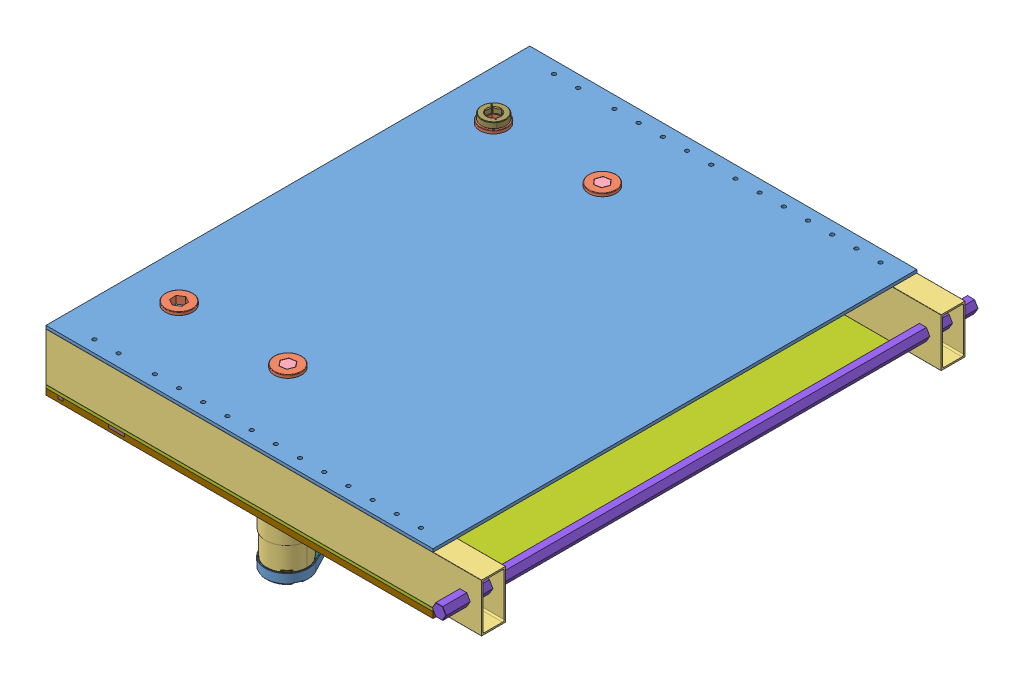
SolidWorks assembly ShooterAssem3, configuration Default. Lengths in mm.
Overall size (477.37 191.98 558.8).
70 component instances, 21 part files, 57 mates.
Components (placement in the parent):
- ShooterPlate3-1: ShooterPlate3 [Default] at (-165.1 53.975 0) size (406.4 3.17 508)
- am-2986 FR8ZZ Hex Bearing.step-1: am-2986 FR8ZZ Hex Bearing.step [Default] at (50.8 60.3783 -88.9) x (0.844394 0 -0.535723) z (0 -1 0) size (31.12 31.12 7.93)
- am-2986 FR8ZZ Hex Bearing.step-2: am-2986 FR8ZZ Hex Bearing.step [Default] at (50.8 60.3783 -419.1) x (0.102965 0 -0.994685) z (0 -1 0) size (31.12 31.12 7.93)
- am-2986 FR8ZZ Hex Bearing.step-3: am-2986 FR8ZZ Hex Bearing.step [Default] at (165.1 60.3783 -419.1) x (0.331233 0 -0.943549) z (0 -1 0) size (31.12 31.12 7.93)
- am-2986 FR8ZZ Hex Bearing.step-4: am-2986 FR8ZZ Hex Bearing.step [Default] at (165.1 60.3783 -88.9) x (-0.373075 0 0.927801) z (0 -1 0) size (31.12 31.12 7.93)
- side-4: side [Default] at (457.2 28.575 -495.3) x (0 0 1) z (-1 0 0) size (25.4 50.8 457.2)
- side-5: side [Default] at (457.2 28.575 -12.7) x (0 0 1) z (-1 0 0) size (25.4 50.8 457.2)
- 4in hex shaft-1: 4in hex shaft [Default] at (165.1 -41.2217 -88.9) x (0.616962 0 0.786993) z (0 1 0) size (14.66 12.7 101.6)
- 4in hex shaft-2: 4in hex shaft [Default] at (165.1 60.3783 -419.1) x (0.331233 0 -0.943549) z (0 -1 0) size (14.66 12.7 101.6)
- am-2647 4inWheel 500 Hex REV2-1: am-2647 4inWheel 500 Hex REV2 [Default] at (165.0712 12.1928 -419.0946) x (0 -1 0) z (-0.331233 0 0.943549) size (25.4 101.6 101.6)
  - am-2647 4inWheel 500 Hex REV2.STEP-1: am-2647 4inWheel 500 Hex REV2.STEP [Default] at origin size (25.4 101.6 101.6)
    - 4in Wheel Intergreated Hub 500 HEX.STEP-1: 4in Wheel Intergreated Hub 500 HEX.STEP [Default] at origin size (25.4 92.71 92.71)
    - 4in Tread.STEP-1: 4in Tread.STEP [Default] at origin size (25.4 101.6 101.6)
- am-2647 4inWheel 500 Hex REV2-5: am-2647 4inWheel 500 Hex REV2 [Default] at (165.0928 23.8627 -88.9503) x (0 -1 0) z (0.616962 0 0.786993) size (25.4 101.6 101.6)
  - am-2647 4inWheel 500 Hex REV2.STEP-1: am-2647 4inWheel 500 Hex REV2.STEP [Default] at origin size (25.4 101.6 101.6)
    - 4in Wheel Intergreated Hub 500 HEX.STEP-1: 4in Wheel Intergreated Hub 500 HEX.STEP [Default] at origin size (25.4 92.71 92.71)
    - 4in Tread.STEP-1: 4in Tread.STEP [Default] at origin size (25.4 101.6 101.6)
- am-2647 4inWheel 500 Hex REV2-6: am-2647 4inWheel 500 Hex REV2 [Default] at (50.7732 34.6251 -419.088) x (0 1 0) z (-0.80994 0 -0.586513) size (25.4 101.6 101.6)
  - am-2647 4inWheel 500 Hex REV2.STEP-1: am-2647 4inWheel 500 Hex REV2.STEP [Default] at origin size (25.4 101.6 101.6)
    - 4in Wheel Intergreated Hub 500 HEX.STEP-1: 4in Wheel Intergreated Hub 500 HEX.STEP [Default] at origin size (25.4 92.71 92.71)
    - 4in Tread.STEP-1: 4in Tread.STEP [Default] at origin size (25.4 101.6 101.6)
- am-2647 4inWheel 500 Hex REV2-7: am-2647 4inWheel 500 Hex REV2 [Default] at (50.7752 32.1769 -88.8843) x (0 -1 0) z (0.041753 0 0.999128) size (25.4 101.6 101.6)
  - am-2647 4inWheel 500 Hex REV2.STEP-1: am-2647 4inWheel 500 Hex REV2.STEP [Default] at origin size (25.4 101.6 101.6)
    - 4in Wheel Intergreated Hub 500 HEX.STEP-1: 4in Wheel Intergreated Hub 500 HEX.STEP [Default] at origin size (25.4 92.71 92.71)
    - 4in Tread.STEP-1: 4in Tread.STEP [Default] at origin size (25.4 101.6 101.6)
- am-2986 FR8ZZ Hex Bearing.step-5: am-2986 FR8ZZ Hex Bearing.step [Default] at (165.1 -3.2283 -88.9) x (0.616962 0 0.786993) z (0 1 0) size (31.12 31.12 7.93)
- am-2986 FR8ZZ Hex Bearing.step-7: am-2986 FR8ZZ Hex Bearing.step [Default] at (165.1 -3.2283 -419.1) x (-0.651521 0 -0.758631) z (0 1 0) size (31.12 31.12 7.93)
- ShooterPlate-2: ShooterPlate [Default] at origin size (406.4 3.17 508)
- shooteraxle-1: shooteraxle [Default] at (438.15 28.575 -533.4) size (14.66 12.7 558.8)
- ThickStick-1: ThickStick [Default] at (0 -6.35 -482.6) size (406.4 6.35 25.4)
- ThickStick-2: ThickStick [Default] at (0 -6.35 0) size (406.4 6.35 25.4)
- Falcon Mount-3: Falcon Mount [Default] at (82.6296 -3.175 -315.8887) x (-1 0 0) z (0 0 1) size (63.5 69.85 63.5)
- Falcon 500.step-2: Falcon 500.step [Default] at (50.8796 -41.275 -315.4637) x (0.866939 0.498415 0) z (0 0 -1) size (62.05 60 125.3)
- Falcon 500.step-3: Falcon 500.step [Default] at (50.7615 -41.275 -192.5351) x (-0.940496 0.339804 0) z (0 0 1) size (62.05 60 125.3)
- Clamping Shaft Collar - 1_2 Hex ID (217-2737).step-6: Clamping Shaft Collar - 1_2 Hex ID (217-2737).step [Default] at (50.6812 17.526 -419.186) x (0.912905 0 -0.408172) z (0 -1 0) size (25.39 25.4 6.35)
- Clamping Shaft Collar - 1_2 Hex ID (217-2737).step-7: Clamping Shaft Collar - 1_2 Hex ID (217-2737).step [Default] at (50.8151 49.276 -419.2459) x (-0.102965 0 0.994685) z (0 1 0) size (25.39 25.4 6.35)
- Clamping Shaft Collar - 1_2 Hex ID (217-2737).step-8: Clamping Shaft Collar - 1_2 Hex ID (217-2737).step [Default] at (50.9339 63.5533 -419.1599) x (-0.80994 0 -0.586513) z (0 -1 0) size (25.39 25.4 6.35)
- Motor support-1: Motor support [Default] at (50.8 0 -254) x (0 0 -1) z (-1 0 0) size (508 3.17 76.2)
- 4-1 Banebots-1: 4-1 Banebots [Default] at (165.2512 -45.5736 -88.5598) x (0.998472 0 0.055267) z (0 1 0) size (47.62 47.62 76.19)
- 775pro.step-1: 775pro.step [Default] at (165.2715 -47.6056 -87.7281) x (1 0 0) z (0 1 0) size (44.99 55.15 90.45)
  - 217-6457-000 Rev2.step-1: 217-6457-000 Rev2.step [Default] at (0 0 -66.1) x (1 0 0) z (0 1 0) size (44.99 33.26 55.15)
    - 217-6457-900 Rev1.step-1: 217-6457-900 Rev1.step [Default] at (0 5.3622 0) x (-1 0 0.000693) z (0.000693 0 1) size (41.5 28.13 51.51)
      - 217-6457-901 Rev3_Instruction Config.step-1: 217-6457-901 Rev3_Instruction Config.step [Default] at origin size (41.5 2.36 51.5)
      - 30-45BBS Rev1_SHORTENED CONTACT.step-1: 30-45BBS Rev1_SHORTENED CONTACT.step [Default] at (3.95 14.4494 26.711) x (0 1 0) z (0 0 -1) size (26 3.6 2)
      - 30-45BBS Rev1_SHORTENED CONTACT.step-2: 30-45BBS Rev1_SHORTENED CONTACT.step [Default] at (-3.9748 14.4494 26.711) x (0 1 0) z (0 0 -1) size (26 3.6 2)
      - PA45XX-X Rev1.step-1: PA45XX-X Rev1.step [Default] at (-8.4198 2.3622 73.1531) x (0 1 0) z (-1 0 0) size (24.71 8.41 8.41)
      - PA45XX-X Rev1.step-2: PA45XX-X Rev1.step [Default] at (-0.495 2.3622 73.1531) x (0 1 0) z (-1 0 0) size (24.71 8.41 8.41)
    - 217-6457-001 Rev4.step-1: 217-6457-001 Rev4.step [Default] at origin size (41.49 7.8 41.49)
    - 217-6457-002 Rev7.step-1: 217-6457-002 Rev7.step [Default] at (0 0.05 0) size (44.99 11.5 55.15)
    - 217-9191-008 Rev1.step-1: 217-9191-008 Rev1.step [Default] at (81.4247 7.8 32.3804) x (-0.560945 0 -0.827853) z (0 1 0) size (4.2 4.2 11.81)
    - 217-9191-008 Rev1.step-2: 217-9191-008 Rev1.step [Default] at (32.3804 7.8 -81.4247) x (-0.827853 0 0.560945) z (0 1 0) size (4.2 4.2 11.81)
    - 217-9191-008 Rev1.step-3: 217-9191-008 Rev1.step [Default] at (-81.4247 7.8 -32.3804) x (0.560945 0 0.827853) z (0 1 0) size (4.2 4.2 11.81)
    - 217-9191-008 Rev1.step-4: 217-9191-008 Rev1.step [Default] at (-32.3804 7.8 81.4247) x (0.827853 0 -0.560945) z (0 1 0) size (4.2 4.2 11.81)
  - 217-4347-000 Rev2.step-1: 217-4347-000 Rev2.step [Default] x (0 0 -1) z (-1 0 0) size (88 44.3 44.3)
- 775pro.step-2: 775pro.step [Default] at (165.2715 -47.6056 -420.2719) x (-1 0 0) z (0 1 0) size (44.99 55.15 90.45)
  - 217-6457-000 Rev2.step-1: 217-6457-000 Rev2.step [Default] at (0 0 -66.1) x (1 0 0) z (0 1 0) size (44.99 33.26 55.15)
    - 217-6457-900 Rev1.step-1: 217-6457-900 Rev1.step [Default] at (0 5.3622 0) x (-1 0 0.000693) z (0.000693 0 1) size (41.5 28.13 51.51)
      - 217-6457-901 Rev3_Instruction Config.step-1: 217-6457-901 Rev3_Instruction Config.step [Default] at origin size (41.5 2.36 51.5)
      - 30-45BBS Rev1_SHORTENED CONTACT.step-1: 30-45BBS Rev1_SHORTENED CONTACT.step [Default] at (3.95 14.4494 26.711) x (0 1 0) z (0 0 -1) size (26 3.6 2)
      - 30-45BBS Rev1_SHORTENED CONTACT.step-2: 30-45BBS Rev1_SHORTENED CONTACT.step [Default] at (-3.9748 14.4494 26.711) x (0 1 0) z (0 0 -1) size (26 3.6 2)
      - PA45XX-X Rev1.step-1: PA45XX-X Rev1.step [Default] at (-8.4198 2.3622 73.1531) x (0 1 0) z (-1 0 0) size (24.71 8.41 8.41)
      - PA45XX-X Rev1.step-2: PA45XX-X Rev1.step [Default] at (-0.495 2.3622 73.1531) x (0 1 0) z (-1 0 0) size (24.71 8.41 8.41)
    - 217-6457-001 Rev4.step-1: 217-6457-001 Rev4.step [Default] at origin size (41.49 7.8 41.49)
    - 217-6457-002 Rev7.step-1: 217-6457-002 Rev7.step [Default] at (0 0.05 0) size (44.99 11.5 55.15)
    - 217-9191-008 Rev1.step-1: 217-9191-008 Rev1.step [Default] at (81.4247 7.8 32.3804) x (-0.560945 0 -0.827853) z (0 1 0) size (4.2 4.2 11.81)
    - 217-9191-008 Rev1.step-2: 217-9191-008 Rev1.step [Default] at (32.3804 7.8 -81.4247) x (-0.827853 0 0.560945) z (0 1 0) size (4.2 4.2 11.81)
    - 217-9191-008 Rev1.step-3: 217-9191-008 Rev1.step [Default] at (-81.4247 7.8 -32.3804) x (0.560945 0 0.827853) z (0 1 0) size (4.2 4.2 11.81)
    - 217-9191-008 Rev1.step-4: 217-9191-008 Rev1.step [Default] at (-32.3804 7.8 81.4247) x (0.827853 0 -0.560945) z (0 1 0) size (4.2 4.2 11.81)
  - 217-4347-000 Rev2.step-1: 217-4347-000 Rev2.step [Default] x (0 0 -1) z (-1 0 0) size (88 44.3 44.3)
- 4-1 Banebots-2: 4-1 Banebots [Default] at (165.2512 -45.5736 -419.4402) x (-0.998472 0 0.055267) z (0 1 0) size (47.62 47.62 76.19)
Mates (geometry in assembly coordinates):
- Coincident23: coincident aligned: plane of ShooterPlate3-1 through (-165.1 57.15 -508) normal (0 0 -1); plane of side-4 through (0 3.429 -508) normal (0 0 -1)
- Coincident24: coincident anti-aligned: plane of ShooterPlate3-1 through (-165.1 53.975 0) normal (0 -1 0); plane of side-4 through (0 53.975 -507.746) normal (0 1 0)
- Coincident26: coincident anti-aligned: plane of ShooterPlate3-1 through (-165.1 53.975 0) normal (0 -1 0); plane of side-5 through (0 53.975 -25.146) normal (0 1 0)
- Coincident28: coincident aligned: plane of ShooterPlate3-1 through (-165.1 57.15 0) normal (0 0 1); plane of side-5 through (0 53.721 0) normal (0 0 1)
- Concentric1: concentric aligned: cylinder of ShooterPlate3-1 through (165.1 53.975 -419.1) axis (0 1 0) radius 14.2875; cylinder of am-2986 FR8ZZ Hex Bearing.step-3 through (165.1 52.451 -419.1) axis (0 1 0) radius 14.2875
- Coincident33: coincident anti-aligned: plane of ShooterPlate3-1 through (-165.1 53.975 0) normal (0 -1 0); plane of am-2986 FR8ZZ Hex Bearing.step-3 through (169.7273 53.975 -432.2814) normal (0 1 0)
- Concentric3: concentric aligned: cylinder of ShooterPlate3-1 through (165.1 53.975 -88.9) axis (0 1 0) radius 14.2875; cylinder of am-2986 FR8ZZ Hex Bearing.step-4 through (165.1 52.451 -88.9) axis (0 1 0) radius 14.2875
- Coincident35: coincident anti-aligned: plane of ShooterPlate3-1 through (-165.1 53.975 0) normal (0 -1 0); plane of am-2986 FR8ZZ Hex Bearing.step-4 through (159.8881 53.975 -75.9386) normal (0 1 0)
- Concentric4: concentric aligned: cylinder of ShooterPlate3-1 through (50.8 53.975 -88.9) axis (0 1 0) radius 14.2875; cylinder of am-2986 FR8ZZ Hex Bearing.step-1 through (50.8 52.451 -88.9) axis (0 1 0) radius 14.2875
- Coincident36: coincident anti-aligned: plane of ShooterPlate3-1 through (-165.1 53.975 0) normal (0 -1 0); plane of am-2986 FR8ZZ Hex Bearing.step-1 through (62.5962 53.975 -96.384) normal (0 1 0)
- Coincident38: coincident anti-aligned: plane of am-2986 FR8ZZ Hex Bearing.step-3 through (162.6713 52.451 -412.1816) normal (-0.184918 0 -0.982754); plane of 4in hex shaft-2 through (162.6713 -41.2217 -412.1816) normal (0.184918 0 0.982754)
- Coincident41: coincident aligned: plane of am-2986 FR8ZZ Hex Bearing.step-3 through (165.1 60.3783 -419.1) normal (0 1 0); plane of 4in hex shaft-2 through (165.1 60.3783 -419.1) normal (0 1 0)
- Coincident42: coincident anti-aligned: plane of am-2986 FR8ZZ Hex Bearing.step-3 through (157.8941 52.451 -417.7441) normal (0.758631 0 -0.651521); plane of 4in hex shaft-2 through (157.8941 -41.2217 -417.7441) normal (-0.758631 0 0.651521)
- Coincident43: coincident aligned: plane of am-2986 FR8ZZ Hex Bearing.step-4 through (165.1 60.3783 -88.9) normal (0 1 0); plane of 4in hex shaft-1 through (165.1 60.3783 -88.9) normal (0 1 0)
- Coincident44: coincident anti-aligned: plane of am-2986 FR8ZZ Hex Bearing.step-4 through (160.5762 52.451 -94.6705) normal (0.927801 0 0.373075); plane of 4in hex shaft-1 through (157.8407 60.3783 -87.8675) normal (-0.927801 0 -0.373075)
- Coincident45: coincident anti-aligned: plane of am-2986 FR8ZZ Hex Bearing.step-4 through (172.3593 52.451 -89.9325) normal (-0.786993 0 0.616962); plane of 4in hex shaft-1 through (167.8355 60.3783 -95.703) normal (0.786993 0 -0.616962)
- Coincident66: coincident anti-aligned: plane of 4in hex shaft-1 through (162.3645 60.3783 -82.097) normal (-0.786993 0 0.616962); plane of am-2647 4inWheel 500 Hex REV2-5/am-2647 4inWheel 500 Hex REV2.STEP-1/4in Wheel Intergreated Hub 500 HEX.STEP-1 through (162.3464 37.7868 -82.1201) normal (0.786993 0 -0.616962)
- Coincident67: coincident anti-aligned: plane of 4in hex shaft-1 through (172.3593 60.3783 -89.9325) normal (0.927801 0 0.373075); plane of am-2647 4inWheel 500 Hex REV2-5/am-2647 4inWheel 500 Hex REV2.STEP-1/4in Wheel Intergreated Hub 500 HEX.STEP-1 through (172.3812 37.7868 -89.9869) normal (-0.927801 0 -0.373075)
- Coincident70: coincident anti-aligned: plane of 4in hex shaft-2 through (172.3059 -41.2217 -420.4559) normal (0.758631 0 -0.651521); plane of am-2647 4inWheel 500 Hex REV2-1/am-2647 4inWheel 500 Hex REV2.STEP-1/4in Wheel Intergreated Hub 500 HEX.STEP-1 through (167.5096 26.1169 -426.0407) normal (-0.758631 0 0.651521)
- Coincident71: coincident anti-aligned: plane of 4in hex shaft-2 through (169.8772 -41.2217 -413.5375) normal (0.943549 0 0.331233); plane of am-2647 4inWheel 500 Hex REV2-1/am-2647 4inWheel 500 Hex REV2.STEP-1/4in Wheel Intergreated Hub 500 HEX.STEP-1 through (172.3059 26.1169 -420.4559) normal (-0.943549 0 -0.331233)
- Coincident73: coincident anti-aligned: plane of 4in hex shaft-1 through (172.3593 60.3783 -89.9325) normal (0.927801 0 0.373075); plane of am-2986 FR8ZZ Hex Bearing.step-5 through (172.3593 4.699 -89.9325) normal (-0.927801 0 -0.373075)
- Coincident74: coincident anti-aligned: plane of 4in hex shaft-1 through (160.5762 60.3783 -94.6705) normal (-0.140809 0 -0.990037); plane of am-2986 FR8ZZ Hex Bearing.step-5 through (160.5762 4.699 -94.6705) normal (0.140809 0 0.990037)
- Coincident87: coincident anti-aligned: plane of side-5 through (0 3.175 -0.254) normal (0 -1 0); plane of ShooterPlate-2 through (0 3.175 0) normal (0 1 0)
- Coincident88: coincident aligned: plane of side-5 through (0 53.721 -0.254) normal (-1 0 0); plane of ShooterPlate-2 through (0 3.175 0) normal (-1 0 0)
- Coincident91: coincident anti-aligned: plane of am-2986 FR8ZZ Hex Bearing.step-5 through (173.719 3.175 -77.9057) normal (0 -1 0); plane of ShooterPlate-2 through (0 3.175 0) normal (0 1 0)
- Coincident96: coincident anti-aligned: plane of 4in hex shaft-2 through (167.5287 -41.2217 -426.0184) normal (-0.184918 0 -0.982754); plane of am-2986 FR8ZZ Hex Bearing.step-7 through (160.3228 4.699 -424.6625) normal (0.184918 0 0.982754)
- Coincident97: coincident anti-aligned: plane of 4in hex shaft-2 through (160.3228 -41.2217 -424.6625) normal (-0.943549 0 -0.331233); plane of am-2986 FR8ZZ Hex Bearing.step-7 through (157.8941 4.699 -417.7441) normal (0.943549 0 0.331233)
- Coincident98: coincident anti-aligned: plane of am-2986 FR8ZZ Hex Bearing.step-7 through (155.9983 3.175 -429.6981) normal (0 -1 0); plane of ShooterPlate-2 through (0 3.175 0) normal (0 1 0)
- Coincident100: coincident anti-aligned: plane of side-4 through (434.4838 22.225 -482.6) normal (0.866025 0.5 0); plane of shooteraxle-1 through (434.4838 22.225 25.4) normal (-0.866025 -0.5 0)
- Coincident101: coincident anti-aligned: plane of side-4 through (441.8162 22.225 -482.6) normal (0 1 0); plane of shooteraxle-1 through (441.8162 22.225 25.4) normal (0 -1 0)
- Distance1: distance = 25.4 mm aligned: plane of side-4 through (0 3.429 -508) normal (0 0 -1); plane of shooteraxle-1 through (438.15 28.575 -533.4) normal (0 0 -1)
- Coincident103: coincident anti-aligned: plane of ShooterPlate-2 through (0 0 0) normal (0 -1 0); plane of ThickStick-1 through (0 0 -482.6) normal (0 1 0)
- Coincident104: coincident aligned: plane of ShooterPlate-2 through (406.4 3.175 0) normal (1 0 0); plane of ThickStick-1 through (406.4 0 -482.6) normal (1 0 0)
- Coincident105: coincident aligned: plane of ShooterPlate-2 through (0 3.175 -508) normal (0 0 -1); plane of ThickStick-1 through (0 0 -508) normal (0 0 -1)
- Coincident106: coincident anti-aligned: plane of ShooterPlate-2 through (0 0 0) normal (0 -1 0); plane of ThickStick-2 through (0 0 0) normal (0 1 0)
- Coincident107: coincident aligned: plane of ShooterPlate-2 through (406.4 3.175 0) normal (1 0 0); plane of ThickStick-2 through (406.4 0 0) normal (1 0 0)
- Coincident108: coincident aligned: plane of ShooterPlate-2 through (0 3.175 0) normal (0 0 1); plane of ThickStick-2 through (0 0 0) normal (0 0 1)
- Coincident116: coincident aligned: plane of side-4 through (0 3.429 -508) normal (0 0 -1); plane of ShooterPlate-2 through (0 3.175 -508) normal (0 0 -1)
- Coincident126: coincident anti-aligned: plane of Falcon Mount-3 through (82.6296 -73.025 -376.2137) normal (0 0 1); plane of Falcon 500.step-2 through (42.6395 -36.4974 -376.2137) normal (0 0 -1)
- Concentric6: concentric aligned: cylinder of Falcon Mount-3 through (50.8796 -41.275 -376.2137) axis (0 0 -1) radius 10.16; cone of Falcon 500.step-2 through (50.8796 -41.275 -376.2137) axis (0 0 -1)
- Coincident132: coincident anti-aligned: plane of side-5 through (0 53.721 0) normal (0 0 1); plane of 775 motor mount-4 through (191.75 8.477 0) normal (0 0 -1)
- Coincident133: coincident aligned: plane of ThickStick-2 through (0 -6.35 0) normal (0 -1 0); plane of 775 motor mount-4 through (191.75 -60.325 61.468) normal (0 -1 0)
- Parallel2: parallel aligned: plane of ShooterPlate-2 through (0 3.175 0) normal (-1 0 0); plane of Falcon Mount-3 through (19.1296 -6.35 -315.8887) normal (-1 0 0)
- Concentric13: concentric aligned: cylinder of am-2986 FR8ZZ Hex Bearing.step-2 through (50.8 52.451 -419.1) axis (0 1 0) radius 14.2875; cylinder of ShooterPlate3-1 through (50.8 53.975 -419.1) axis (0 1 0) radius 14.2875
- Coincident169: coincident anti-aligned: plane of ShooterPlate3-1 through (-165.1 53.975 0) normal (0 -1 0); plane of am-2986 FR8ZZ Hex Bearing.step-2 through (52.2384 53.975 -432.9957) normal (0 1 0)
- Coincident176: coincident anti-aligned: plane of am-2647 4inWheel 500 Hex REV2-6/am-2647 4inWheel 500 Hex REV2.STEP-1/4in Wheel Intergreated Hub 500 HEX.STEP-1 through (54.4976 20.701 -424.2311) normal (0 -1 0); plane of Clamping Shaft Collar - 1_2 Hex ID (217-2737).step-6 through (50.6812 20.701 -419.186) normal (0 1 0)
- Coincident180: coincident anti-aligned: plane of am-2647 4inWheel 500 Hex REV2-6/am-2647 4inWheel 500 Hex REV2.STEP-1/4in Wheel Intergreated Hub 500 HEX.STEP-1 through (54.4976 46.101 -424.2311) normal (0 1 0); plane of Clamping Shaft Collar - 1_2 Hex ID (217-2737).step-7 through (50.8151 46.101 -419.2459) normal (0 -1 0)
- Coincident183: coincident anti-aligned: plane of am-2986 FR8ZZ Hex Bearing.step-2 through (50.8 60.3783 -419.1) normal (0 1 0); plane of Clamping Shaft Collar - 1_2 Hex ID (217-2737).step-8 through (50.9339 60.3783 -419.1599) normal (0 -1 0)
- Coincident185: coincident aligned: plane of ShooterPlate3-1 through (406.4 57.15 0) normal (1 0 0); plane of ShooterPlate-2 through (406.4 3.175 0) normal (1 0 0)
- Coincident186: coordinate: point of ShooterPlate-2
- Coincident187: coincident aligned: plane of side-4 through (0 53.721 -482.854) normal (-1 0 0); plane of ShooterPlate-2 through (0 3.175 0) normal (-1 0 0)
- Coincident188: coincident anti-aligned: plane of ShooterPlate-2 through (0 0 0) normal (0 -1 0); plane of Motor support-1 through (50.8 0 -254) normal (0 1 0)
- Coincident189: coincident aligned: plane of side-4 through (0 3.429 -508) normal (0 0 -1); plane of Motor support-1 through (12.7 -3.175 -508) normal (0 0 -1)
- Distance8: distance = 12.7 mm aligned: plane of Motor support-1 through (12.7 -3.175 -508) normal (-1 0 0); plane of ShooterPlate-2 through (0 3.175 0) normal (-1 0 0)
- Coincident193: coincident anti-aligned: plane of Falcon Mount-3 through (82.6296 -3.175 -315.8887) normal (0 1 0); plane of Motor support-1 through (50.8 -3.175 -254) normal (0 -1 0)
- Coincident201: coincident anti-aligned: plane of am-2986 FR8ZZ Hex Bearing.step-2 through (52.4019 52.451 -434.5748) normal (0 -1 0); plane of Clamping Shaft Collar - 1_2 Hex ID (217-2737).step-7 through (50.8151 52.451 -419.2459) normal (0 1 0)
- Coincident218: coincident anti-aligned: plane of 4-1 Banebots-1 through (141.8318 -47.6056 -67.5971) normal (0 -1 0); plane of 775pro.step-1/217-4347-000 Rev2.step-1 through (165.2715 -47.6056 -78.9781) normal (0 1 0)
